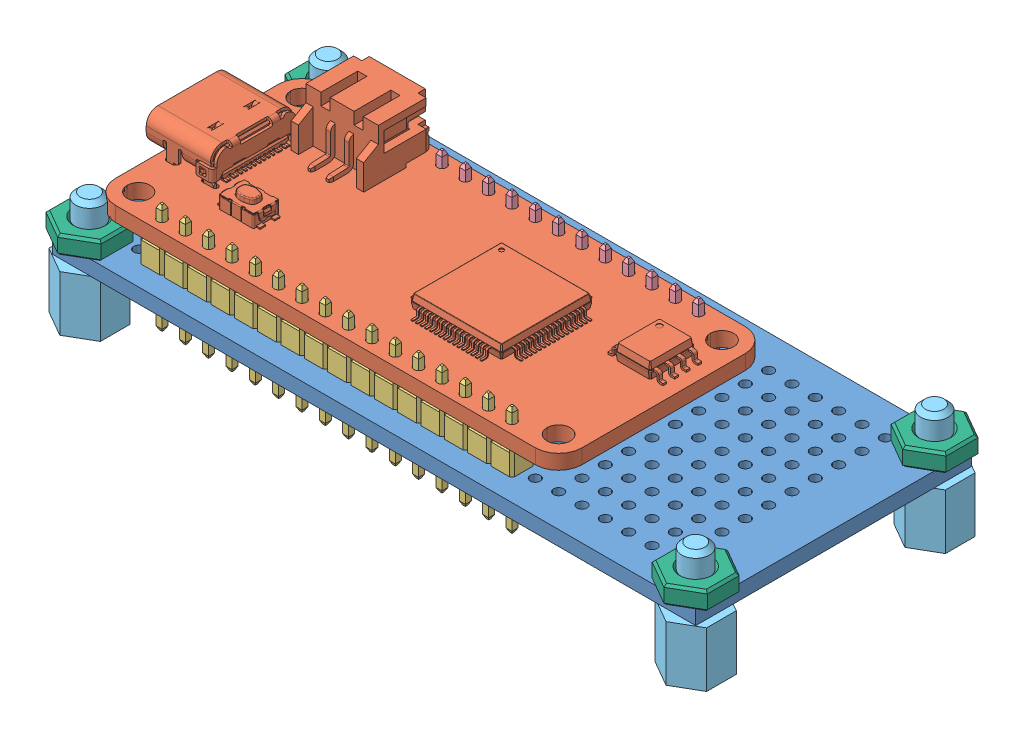
SolidWorks assembly feather-with-protoboard, configuration Default. Lengths in mm.
Overall size (72 17.29 32.93).
16 component instances, 6 part files, 33 mates.
Components (placement in the parent):
- protoboard-70x30-1: protoboard-70x30 [Default] at origin size (70 1.6 30)
- adafruit-feather-1: adafruit-feather [Default] at (-156.1211 4.14 -103.7336) x (1 0 0) z (0 1 0) size (51.99 22.86 7.15)
- pinheader-2.54mm-male-16-1: pinheader-2.54mm-male-16 [Default] at (-26.67 4.14 11.43) x (1 0 0) z (0 -1 0) size (40.64 2.54 11.94)
  - 16-Pin Header - Male - 2.54mm(2)^pinheader-2.54mm-male-16-1: 16-Pin Header - Male - 2.54mm(2)^pinheader-2.54mm-male-16 [Default] at origin size (40.64 2.54 11.94) (virtual)
    - 16-Pin Header - Male - 2.54mm(2)^16-Pin Header - Male - 2.54mm(2)_pinheader-2.54mm-male-16-1: 16-Pin Header - Male - 2.54mm(2)^16-Pin Header - Male - 2.54mm(2)_pinheader-2.54mm-male-16 [Default] x (1 0 0) z (0 -1 0) size (40.64 11.94 2.54) (virtual)
- pinheader-2.54mm-male-12-1: pinheader-2.54mm-male-12 [Default] at (11.43 4.14 -8.89) x (-1 0 0) z (0 -1 0) size (30.48 2.54 11.94)
  - 12-Pin Header - Male - 2.54mm(2)^pinheader-2.54mm-male-12-1: 12-Pin Header - Male - 2.54mm(2)^pinheader-2.54mm-male-12 [Default] at origin size (30.48 2.54 11.94) (virtual)
    - 12-Pin Header - Male - 2.54mm(2)^12-Pin Header - Male - 2.54mm(2)_pinheader-2.54mm-male-12-1: 12-Pin Header - Male - 2.54mm(2)^12-Pin Header - Male - 2.54mm(2)_pinheader-2.54mm-male-12 [Default] x (1 0 0) z (0 -1 0) size (30.48 11.94 2.54) (virtual)
- spacer-nylon-6mm-M3-1: spacer-nylon-6mm-M3 [Default] at (-33 -6 13) size (5.6 11.9 6.47)
- spacer-nylon-6mm-M3-2: spacer-nylon-6mm-M3 [Default] at (-33 -6 -13) size (5.6 11.9 6.47)
- spacer-nylon-6mm-M3-3: spacer-nylon-6mm-M3 [Default] at (33 -6 13) size (5.6 11.9 6.47)
- spacer-nylon-6mm-M3-4: spacer-nylon-6mm-M3 [Default] at (33 -6 -13) size (5.6 11.9 6.47)
- nut-M3-1: nut-M3 [Default] at (-33 1.6 13) size (6 2 6.93)
- nut-M3-2: nut-M3 [Default] at (-33 1.6 -13) size (6 2 6.93)
- nut-M3-3: nut-M3 [Default] at (33 1.6 13) size (6 2 6.93)
- nut-M3-4: nut-M3 [Default] at (33 1.6 -13) size (6 2 6.93)
Mates (geometry in assembly coordinates):
- Coincident2: coincident anti-aligned: plane of protoboard-70x30-1 through (0 1.6 0) normal (0 1 0); plane of pinheader-2.54mm-male-16-1/16-Pin Header - Male - 2.54mm(2)^pinheader-2.54mm-male-16-1/16-Pin Header - Male - 2.54mm(2)^16-Pin Header - Male - 2.54mm(2)_pinheader-2.54mm-male-16-1 through (-26.67 1.6 11.43) normal (0 -1 0)
- Coincident3: coincident anti-aligned: plane of protoboard-70x30-1 through (0 1.6 0) normal (0 1 0); plane of pinheader-2.54mm-male-12-1/12-Pin Header - Male - 2.54mm(2)^pinheader-2.54mm-male-12-1/12-Pin Header - Male - 2.54mm(2)^12-Pin Header - Male - 2.54mm(2)_pinheader-2.54mm-male-12-1 through (11.43 1.6 -8.89) normal (0 -1 0)
- Concentric7: concentric aligned: cylinder of protoboard-70x30-1 through (-26.67 -0.001 11.43) axis (0 1 0) radius 0.55; line of pinheader-2.54mm-male-16-1 through (-26.67 -6.6232 11.43) axis (0 1 0)
- Concentric8: concentric aligned: cylinder of protoboard-70x30-1 through (11.43 -0.001 11.43) axis (0 1 0) radius 0.55; line of pinheader-2.54mm-male-16-1 through (11.43 -7.6104 11.43) axis (0 1 0)
- Concentric9: concentric aligned: cylinder of adafruit-feather-1 through (-26.67 3.34 11.43) axis (0 1 0) radius 0.5; line of pinheader-2.54mm-male-16-1 through (-26.67 -6.6232 11.43) axis (0 1 0)
- Concentric10: concentric aligned: cylinder of adafruit-feather-1 through (11.43 3.34 11.43) axis (0 1 0) radius 0.5; line of pinheader-2.54mm-male-16-1 through (11.43 -7.6104 11.43) axis (0 1 0)
- Concentric11: concentric anti-aligned: cylinder of protoboard-70x30-1 through (-16.51 -0.001 -8.89) axis (0 1 0) radius 0.55; line of pinheader-2.54mm-male-12-1 through (-16.51 8.5354 -8.89) axis (0 -1 0)
- Concentric12: concentric aligned: cylinder of protoboard-70x30-1 through (11.43 -0.001 -8.89) axis (0 1 0) radius 0.55; line of pinheader-2.54mm-male-12-1 through (11.43 -7.0406 -8.89) axis (0 1 0)
- Coincident4: coincident anti-aligned: plane of adafruit-feather-1 through (-7.62 4.14 1.27) normal (0 -1 0); plane of pinheader-2.54mm-male-16-1/16-Pin Header - Male - 2.54mm(2)^pinheader-2.54mm-male-16-1/16-Pin Header - Male - 2.54mm(2)^16-Pin Header - Male - 2.54mm(2)_pinheader-2.54mm-male-16-1 through (-26.67 4.14 11.43) normal (0 1 0)
- Concentric13: concentric aligned: cylinder of protoboard-70x30-1 through (-33 1.6 13) axis (0 -1 0) radius 1.5; cylinder of spacer-nylon-6mm-M3-1 through (-33 5.9 13) axis (0 -1 0) radius 1.5
- Coincident5: coincident anti-aligned: plane of protoboard-70x30-1 through (0 0 0) normal (0 -1 0); plane of spacer-nylon-6mm-M3-1 through (-33 0 13) normal (0 1 0)
- Parallel1: parallel aligned: plane of protoboard-70x30-1 through (-35 1.6 -15) normal (-1 0 0); plane of spacer-nylon-6mm-M3-1 through (-35.8 0 11.3834) normal (-1 0 0)
- Concentric14: concentric aligned: cylinder of protoboard-70x30-1 through (-33 1.6 -13) axis (0 -1 0) radius 1.5; cylinder of spacer-nylon-6mm-M3-2 through (-33 5.9 -13) axis (0 -1 0) radius 1.5
- Coincident7: coincident anti-aligned: plane of protoboard-70x30-1 through (0 0 0) normal (0 -1 0); plane of spacer-nylon-6mm-M3-2 through (-33 0 -13) normal (0 1 0)
- Parallel2: parallel aligned: plane of protoboard-70x30-1 through (-35 1.6 -15) normal (-1 0 0); plane of spacer-nylon-6mm-M3-2 through (-35.8 0 -14.6166) normal (-1 0 0)
- Coincident8: coincident anti-aligned: plane of protoboard-70x30-1 through (0 0 0) normal (0 -1 0); plane of spacer-nylon-6mm-M3-3 through (33 0 13) normal (0 1 0)
- Parallel3: parallel aligned: plane of protoboard-70x30-1 through (-35 1.6 -15) normal (-1 0 0); plane of spacer-nylon-6mm-M3-3 through (30.2 0 11.3834) normal (-1 0 0)
- Concentric15: concentric aligned: cylinder of protoboard-70x30-1 through (33 1.6 13) axis (0 -1 0) radius 1.5; cylinder of spacer-nylon-6mm-M3-3 through (33 5.9 13) axis (0 -1 0) radius 1.5
- Coincident9: coincident anti-aligned: plane of protoboard-70x30-1 through (0 0 0) normal (0 -1 0); plane of spacer-nylon-6mm-M3-4 through (33 0 -13) normal (0 1 0)
- Parallel4: parallel aligned: plane of protoboard-70x30-1 through (-35 1.6 -15) normal (-1 0 0); plane of spacer-nylon-6mm-M3-4 through (30.2 0 -14.6166) normal (-1 0 0)
- Concentric16: concentric aligned: cylinder of protoboard-70x30-1 through (33 1.6 -13) axis (0 -1 0) radius 1.5; cylinder of spacer-nylon-6mm-M3-4 through (33 5.9 -13) axis (0 -1 0) radius 1.5
- Concentric17: concentric aligned: cylinder of spacer-nylon-6mm-M3-1 through (-33 5.9 13) axis (0 -1 0) radius 1.5; cylinder of nut-M3-1 through (-33 3.6 13) axis (0 -1 0) radius 1.5
- Coincident11: coincident anti-aligned: plane of protoboard-70x30-1 through (0 1.6 0) normal (0 1 0); plane of nut-M3-1 through (-33 1.6 13) normal (0 -1 0)
- Parallel6: parallel aligned: plane of protoboard-70x30-1 through (-35 1.6 -15) normal (-1 0 0); plane of nut-M3-1 through (-36 3.6 11.2679) normal (-1 0 0)
- Concentric18: concentric aligned: cylinder of spacer-nylon-6mm-M3-2 through (-33 5.9 -13) axis (0 -1 0) radius 1.5; cylinder of nut-M3-2 through (-33 3.6 -13) axis (0 -1 0) radius 1.5
- Coincident13: coincident anti-aligned: plane of protoboard-70x30-1 through (0 1.6 0) normal (0 1 0); plane of nut-M3-2 through (-33 1.6 -13) normal (0 -1 0)
- Parallel7: parallel aligned: plane of protoboard-70x30-1 through (-35 1.6 -15) normal (-1 0 0); plane of nut-M3-2 through (-36 3.6 -14.7321) normal (-1 0 0)
- Coincident14: coincident anti-aligned: plane of protoboard-70x30-1 through (0 1.6 0) normal (0 1 0); plane of nut-M3-3 through (33 1.6 13) normal (0 -1 0)
- Parallel8: parallel aligned: plane of protoboard-70x30-1 through (-35 1.6 -15) normal (-1 0 0); plane of nut-M3-3 through (30 3.6 11.2679) normal (-1 0 0)
- Concentric19: concentric aligned: cylinder of spacer-nylon-6mm-M3-3 through (33 5.9 13) axis (0 -1 0) radius 1.5; cylinder of nut-M3-3 through (33 3.6 13) axis (0 -1 0) radius 1.5
- Coincident15: coincident anti-aligned: plane of protoboard-70x30-1 through (0 1.6 0) normal (0 1 0); plane of nut-M3-4 through (33 1.6 -13) normal (0 -1 0)
- Parallel9: parallel aligned: plane of protoboard-70x30-1 through (-35 1.6 -15) normal (-1 0 0); plane of nut-M3-4 through (30 3.6 -14.7321) normal (-1 0 0)
- Concentric20: concentric aligned: cylinder of spacer-nylon-6mm-M3-4 through (33 5.9 -13) axis (0 -1 0) radius 1.5; cylinder of nut-M3-4 through (33 3.6 -13) axis (0 -1 0) radius 1.5
